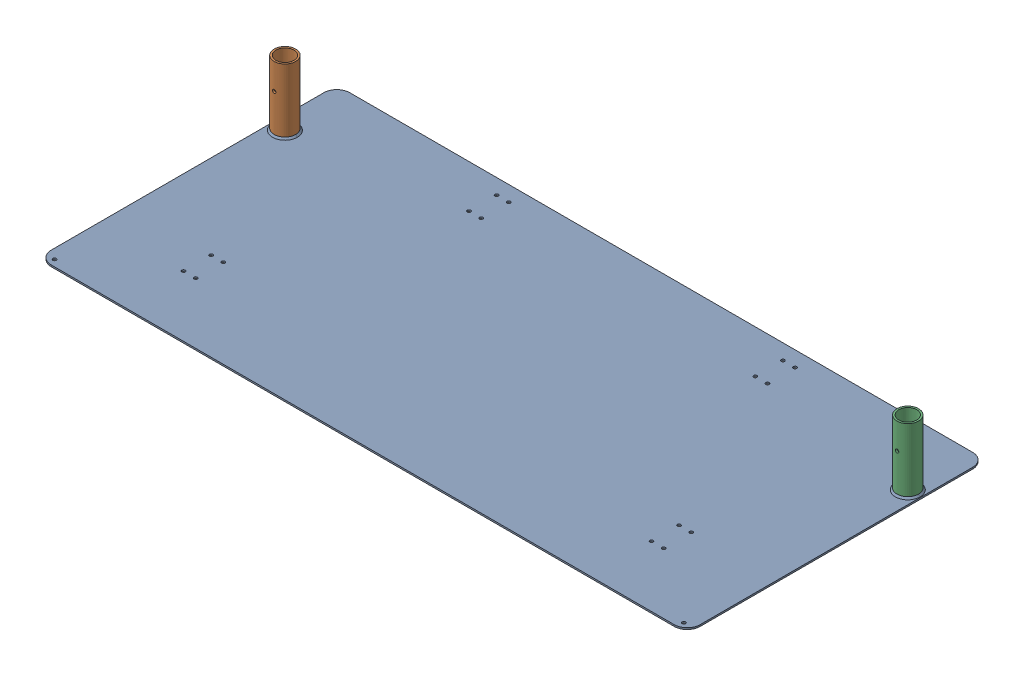
SolidWorks assembly GE-16031_ASM, configuration Default. Lengths in mm.
Overall size (1270 130.18 584.2).
4 component instances, 3 part files, 0 mates.
Components (placement in the parent):
- GE-16031_ASM-1: GE-16031_ASM [Default] at origin size (1267.79 3.23 49.21)
- GE-16016-1: GE-16016 [Default] at origin size (1270 3.17 584.2)
- GE-16031-01-1: GE-16031-01 [Default] at (-609.6 3.175 -165.1) size (42.16 127 42.16)
- GE-16031-01-2: GE-16031-01 [Default] at (609.6 3.175 -165.1) size (42.16 127 42.16)
